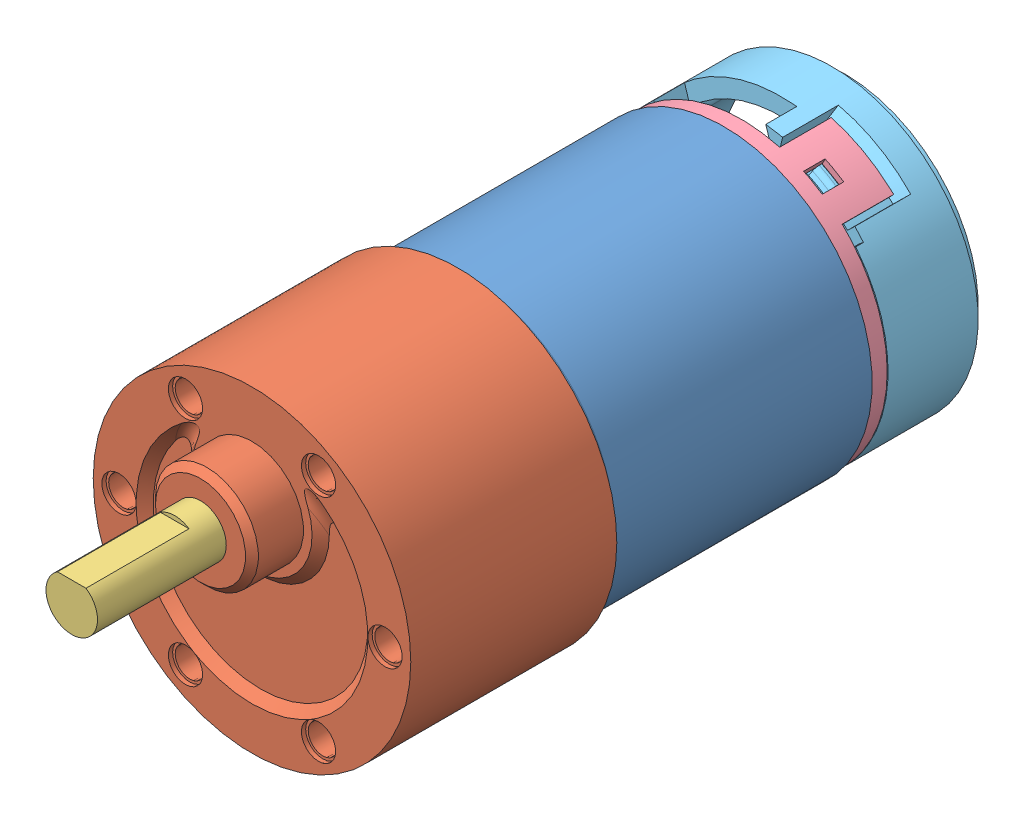
SolidWorks assembly Motor_w_Encoder_Cap_M_rev1, configuration Default. Lengths in mm.
Overall size (42.65 42.65 90).
5 component instances, 5 part files, 13 mates.
Components (placement in the parent):
- Motor_rev0-1: Motor_rev0 [Default] at (12.0471 18.5029 10.1025) size (34.5 34.5 31)
- Gearbox_rev0-1: Gearbox_rev0 [Default] at (12.0471 18.5029 41.1025) size (37 37 30)
- Shaft_rev0-1: Shaft_rev0 [Default] at (12.0471 25.5029 65.1025) size (6 6 21)
- Back_Motor_Cover_rev0-1: Back_Motor_Cover_rev0 [Default] at (12.0471 18.5029 10.1025) x (0.953717 0.300706 0) z (0 0 -1) size (34 34 8)
- Encoder_Cap_M_rev0-2-1: Encoder_Cap_M_rev0-2 [Default] at (12.0471 18.5029 -2.4975) x (-0.953717 -0.300706 0) z (0 0 1) size (34 34 11.9)
Mates (geometry in assembly coordinates):
- Coincident1: coincident anti-aligned: plane of Motor_rev0-1 through (12.0471 18.5029 41.1025) normal (0 0 1); plane of Gearbox_rev0-1 through (12.0471 18.5029 41.1025) normal (0 0 -1)
- Concentric1: concentric aligned: cylinder of Motor_rev0-1 through (12.0471 18.5029 41.1025) axis (0 0 -1) radius 17.25; cylinder of Gearbox_rev0-1 through (12.0471 18.5029 65.1025) axis (0 0 -1) radius 18.5
- Lock1: lock: unknown of Motor_rev0-1; unknown of Gearbox_rev0-1
- Hinge1: hinge anti-aligned: cylinder of Gearbox_rev0-1 through (12.0471 25.5029 71.1025) axis (0 0 -1) radius 3; cylinder of Shaft_rev0-1 through (12.0471 25.5029 86.1025) axis (0 0 -1) radius 3; plane of Gearbox_rev0-1 through (12.0471 18.5029 65.1025) normal (0 0 1); plane of Shaft_rev0-1 through (12.0471 25.5029 65.1025) normal (0 0 -1)
- Coincident2: coincident anti-aligned: plane of Motor_rev0-1 through (12.0471 18.5029 10.1025) normal (0 0 -1); plane of Back_Motor_Cover_rev0-1 through (12.0471 18.5029 10.1025) normal (0 0 1)
- Concentric2: concentric anti-aligned: cylinder of Motor_rev0-1 through (12.0471 18.5029 41.1025) axis (0 0 -1) radius 17.25; cylinder of Back_Motor_Cover_rev0-1 through (12.0471 18.5029 8.1025) axis (0 0 1) radius 17
- Coincident3: coincident aligned: plane of Shaft_rev0-1 through (12.0471 25.5029 65.1025) normal (1 0 0); plane of Back_Motor_Cover_rev0-1 through (12.0471 18.5029 10.1025) normal (1 0 0)
- Coincident4: coincident anti-aligned: plane of Back_Motor_Cover_rev0-1 through (12.0471 18.5029 7.1025) normal (0 0 -1); plane of Encoder_Cap_M_rev0-1 through (12.0471 18.5029 7.1025) normal (0 0 1)
- Concentric3: concentric aligned: cylinder of Back_Motor_Cover_rev0-1 through (12.0471 18.5029 2.1025) axis (0 0 1) radius 16.25; cylinder of Encoder_Cap_M_rev0-1 through (12.0471 18.5029 0.5025) axis (0 0 1) radius 15.8
- Coincident5: coincident aligned: plane of Back_Motor_Cover_rev0-1 through (12.0471 18.5029 10.1025) normal (0.953717 0.300706 0); plane of Encoder_Cap_M_rev0-1 through (12.0471 18.5029 -2.7475) normal (0.953717 0.300706 0)
- Concentric4: concentric anti-aligned: cylinder of Back_Motor_Cover_rev0-1 through (12.0471 18.5029 8.1025) axis (0 0 1) radius 17; cylinder of Encoder_Cap_M_rev0-2-1 through (12.0471 18.5029 8.0025) axis (0 0 -1) radius 17
- Coincident6: coincident anti-aligned: plane of Back_Motor_Cover_rev0-1 through (12.0471 18.5029 7.1025) normal (0 0 -1); plane of Encoder_Cap_M_rev0-2-1 through (12.0471 18.5029 7.1025) normal (0 0 1)
- Coincident7: coincident aligned: plane of Back_Motor_Cover_rev0-1 through (12.0471 18.5029 10.1025) normal (0.953717 0.300706 0); plane of Encoder_Cap_M_rev0-2-1 through (12.0471 18.5029 -2.4975) normal (0.953717 0.300706 0)
